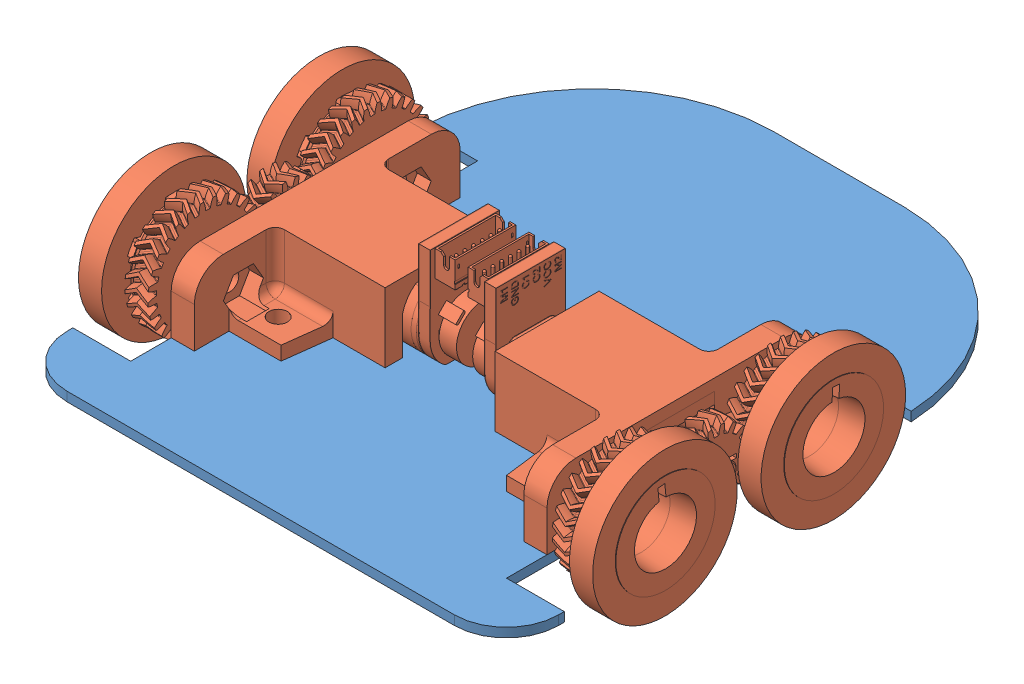
SolidWorks assembly Full Assembly, configuration Default. Lengths in mm.
Overall size (89.27 26 100).
3 component instances, 2 part files, 6 mates.
Components (placement in the parent):
- Base Plate-1: Base Plate [Default] at (36.4751 50.4122 77.8695) size (85 1.6 100)
- Single Motor Unit-1: Single Motor Unit [Default] at (25.9069 31.5421 104.2179) x (0 0 -1) z (1 0 0) size (54 26 43.54)
- Single Motor Unit-2: Single Motor Unit [Default] at (52.0433 31.5421 71.521) x (0 0 1) z (-1 0 0) size (54 26 43.54)
Mates (geometry in assembly coordinates):
- Coincident1: coincident anti-aligned: plane of Base Plate-1 through (22.891 52.0122 59.3166) normal (0 1 0); plane of Single Motor Unit-1 through (71.4751 52.0122 87.8695) normal (0 -1 0)
- Parallel1: parallel aligned: plane of Base Plate-1 through (6.4751 52.0122 57.8695) normal (-1 0 0); plane of Single Motor Unit-1 through (48.4751 64.0122 78.8695) normal (-1 0 0)
- Concentric1: concentric aligned: cylinder of Base Plate-1 through (62.9751 50.4122 74.8695) axis (0 1 0) radius 1.5; cylinder of Single Motor Unit-1 through (62.9751 52.0112 74.8695) axis (0 1 0) radius 1.6
- Coincident3: coincident anti-aligned: plane of Base Plate-1 through (22.891 52.0122 59.3166) normal (0 1 0); plane of Single Motor Unit-2 through (6.4751 52.0122 87.8695) normal (0 -1 0)
- Parallel2: parallel aligned: plane of Base Plate-1 through (71.4751 52.0122 57.8695) normal (1 0 0); plane of Single Motor Unit-2 through (29.4751 64.0122 96.8695) normal (1 0 0)
- Concentric2: concentric aligned: cylinder of Base Plate-1 through (14.9751 50.4122 100.8695) axis (0 1 0) radius 1.5; cylinder of Single Motor Unit-2 through (14.9751 52.0112 100.8695) axis (0 1 0) radius 1.6
